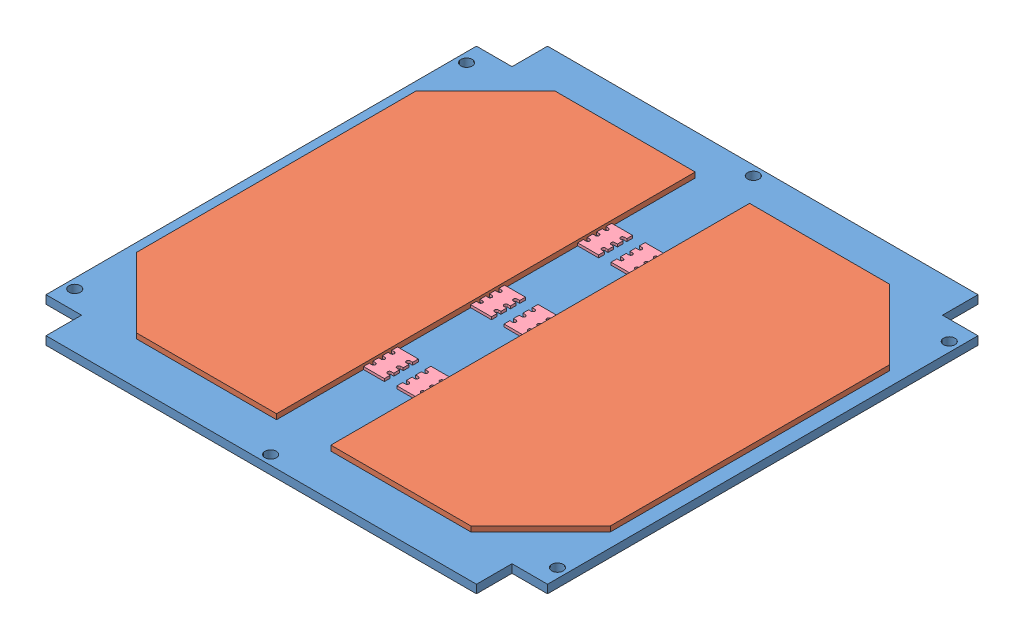
SolidWorks assembly B3_+Z_panel, configuration Default. Lengths in mm.
Overall size (96 7.1 96).
10 component instances, 4 part files, 29 mates.
Components (placement in the parent):
- B3_+Z_panel-1: B3_+Z_panel [Default] at (-207.8501 -0.9 90.2045) size (96 1.6 96)
- Solar panel-1: Solar panel [Default] at (-208.8276 0.7 90.6089) x (0 0 -1) z (1 0 0) size (80.15 1 40.15)
- Solar panel-2: Solar panel [Default] at (-178.7613 1.7 90.6089) x (0 0 -1) z (-1 0 0) size (80.15 1 40.15)
- Solar panel_f-1: Solar panel_f [Default] at (-229.0444 -5.4 135.276) x (-1 0 0) z (0 0 1) size (3.7 4.5 24)
- Solar panel_connector-1: Solar panel_connector [Default] at (-192.5944 1.2 106.501) x (0 0 1) z (1 0 0) size (6.5 0.5 4)
- Solar panel_connector-2: Solar panel_connector [Default] at (-198.9944 1.2 127.001) x (0 0 1) z (1 0 0) size (6.5 0.5 4)
- Solar panel_connector-3: Solar panel_connector [Default] at (-198.9944 1.2 106.501) x (0 0 1) z (1 0 0) size (6.5 0.5 4)
- Solar panel_connector-4: Solar panel_connector [Default] at (-198.9944 1.2 86.001) x (0 0 1) z (1 0 0) size (6.5 0.5 4)
- Solar panel_connector-5: Solar panel_connector [Default] at (-192.5944 1.2 127.001) x (0 0 1) z (1 0 0) size (6.5 0.5 4)
- Solar panel_connector-6: Solar panel_connector [Default] at (-192.5944 1.2 86.001) x (0 0 1) z (1 0 0) size (6.5 0.5 4)
Mates (geometry in assembly coordinates):
- Coincident1: coincident anti-aligned: plane of B3_+Z_panel-1 through (-207.8501 0.7 90.2045) normal (0 1 0); plane of Solar panel-1 through (-208.8276 0.7 90.6089) normal (0 -1 0)
- Coincident20: coincident anti-aligned: plane of B3_+Z_panel-1 through (-207.8501 -0.9 90.2045) normal (0 -1 0); plane of Solar panel_f-1 through (-229.0444 -0.9 135.276) normal (0 1 0)
- Distance24: distance = 83.25 mm aligned: plane of Solar panel_f-1 through (-229.0444 -5.4 111.276) normal (1 0 0); plane of B3_+Z_panel-1 through (-145.7944 -0.9 62.576) normal (1 0 0)
- Distance25: distance = 16.5 mm aligned: plane of Solar panel_f-1 through (-229.0444 -5.4 135.276) normal (0 0 1); plane of B3_+Z_panel-1 through (-152.5944 -0.9 151.776) normal (0 0 1)
- Distance26: distance = 8.125 mm aligned: plane of Solar panel-1 through (-198.9944 1.7 143.651) normal (0 0 1); plane of B3_+Z_panel-1 through (-152.5944 -0.9 151.776) normal (0 0 1)
- Distance27: distance = 2.65 mm aligned: plane of Solar panel-1 through (-239.1444 1.7 130.301) normal (-1 0 0); plane of B3_+Z_panel-1 through (-241.7944 -0.9 144.976) normal (-1 0 0)
- 一致1: coincident anti-aligned: plane of B3_+Z_panel-1 through (-207.8501 0.7 90.2045) normal (0 1 0); plane of Solar panel_connector-2 through (-195.4944 0.7 125.551) normal (0 -1 0)
- 一致2: coincident: plane of Solar panel-1 through (-198.9944 1.7 63.501) normal (1 0 0); line of Solar panel_connector-2 through (-198.9944 1.2 123.401) axis (0 0 -1)
- 一致4: coincident anti-aligned: plane of B3_+Z_panel-1 through (-207.8501 0.7 90.2045) normal (0 1 0); plane of Solar panel_connector-3 through (-195.4944 0.7 105.051) normal (0 -1 0)
- 一致5: coincident: plane of Solar panel-1 through (-198.9944 1.7 63.501) normal (1 0 0); line of Solar panel_connector-3 through (-198.9944 1.2 102.901) axis (0 0 -1)
- 一致6: coincident anti-aligned: plane of B3_+Z_panel-1 through (-207.8501 0.7 90.2045) normal (0 1 0); plane of Solar panel_connector-4 through (-195.4944 0.7 84.551) normal (0 -1 0)
- 一致7: coincident: plane of Solar panel-1 through (-198.9944 1.7 63.501) normal (1 0 0); line of Solar panel_connector-4 through (-198.9944 1.2 82.401) axis (0 0 -1)
- 一致8: coincident anti-aligned: plane of B3_+Z_panel-1 through (-207.8501 0.7 90.2045) normal (0 1 0); plane of Solar panel_connector-1 through (-189.0944 0.7 105.051) normal (0 -1 0)
- 一致10: coincident anti-aligned: plane of B3_+Z_panel-1 through (-207.8501 0.7 90.2045) normal (0 1 0); plane of Solar panel_connector-5 through (-189.0944 0.7 125.551) normal (0 -1 0)
- 一致11: coincident anti-aligned: plane of B3_+Z_panel-1 through (-207.8501 0.7 90.2045) normal (0 1 0); plane of Solar panel_connector-6 through (-189.0944 0.7 84.551) normal (0 -1 0)
- 距離1: distance = 56.4878 mm: point of assembly; line of B3_+Z_panel-1 through (-234.9944 -0.9 55.776) axis (1 0 0)
- 一致13: coincident anti-aligned: plane of B3_+Z_panel-1 through (-207.8501 0.7 90.2045) normal (0 1 0); plane of Solar panel-2 through (-178.7613 0.7 90.6089) normal (0 -1 0)
- 平行1: parallel anti-aligned: line of Solar panel-1 through (-225.7944 1.7 143.651) axis (1 0 0); line of Solar panel-2 through (-161.7944 1.7 143.651) axis (-1 0 0)
- 一致15: coincident anti-aligned: line of Solar panel-1 through (-198.9944 1.7 63.501) axis (-1 0 0); line of Solar panel-2 through (-188.5944 1.7 63.501) axis (1 0 0)
- 距離3: distance = 2.65 mm aligned: plane of Solar panel-2 through (-148.4444 0.7 130.301) normal (1 0 0); plane of B3_+Z_panel-1 through (-145.7944 -0.9 62.576) normal (1 0 0)
- 一致18: coincident anti-aligned: plane of Solar panel-2 through (-188.5944 0.7 63.501) normal (-1 0 0); plane of Solar panel_connector-6 through (-188.5944 0.7 80.601) normal (1 0 0)
- 一致19: coincident aligned: line of Solar panel_connector-4 through (-198.9944 1.2 79.501) axis (1 0 0); line of Solar panel_connector-6 through (-192.5944 1.2 79.501) axis (1 0 0)
- 一致20: coincident anti-aligned: plane of Solar panel-2 through (-188.5944 0.7 63.501) normal (-1 0 0); plane of Solar panel_connector-1 through (-188.5944 0.7 101.101) normal (1 0 0)
- 一致22: coincident anti-aligned: plane of Solar panel-2 through (-188.5944 0.7 63.501) normal (-1 0 0); plane of Solar panel_connector-5 through (-188.5944 0.7 127.001) normal (1 0 0)
- 一致23: coincident aligned: line of Solar panel_connector-1 through (-192.5944 1.2 100.001) axis (1 0 0); line of Solar panel_connector-3 through (-198.9944 1.2 100.001) axis (1 0 0)
- 一致24: coincident aligned: line of Solar panel_connector-2 through (-198.9944 1.2 120.501) axis (1 0 0); line of Solar panel_connector-5 through (-192.5944 1.2 120.501) axis (1 0 0)
- 距離4: distance = 16 mm: plane of Solar panel-1 through (-225.7944 1.7 63.501) normal (0 0 -1); line of Solar panel_connector-4 through (-198.9944 0.7 79.501) axis (1 0 0)
- 距離5: distance = 36.5 mm aligned: plane of Solar panel-1 through (-225.7944 1.7 63.501) normal (0 0 -1); plane of Solar panel_connector-3 through (-198.9944 0.7 100.001) normal (0 0 -1)
- 距離6: distance = 57 mm aligned: plane of Solar panel_connector-2 through (-198.9944 0.7 120.501) normal (0 0 -1); plane of Solar panel-1 through (-225.7944 1.7 63.501) normal (0 0 -1)
